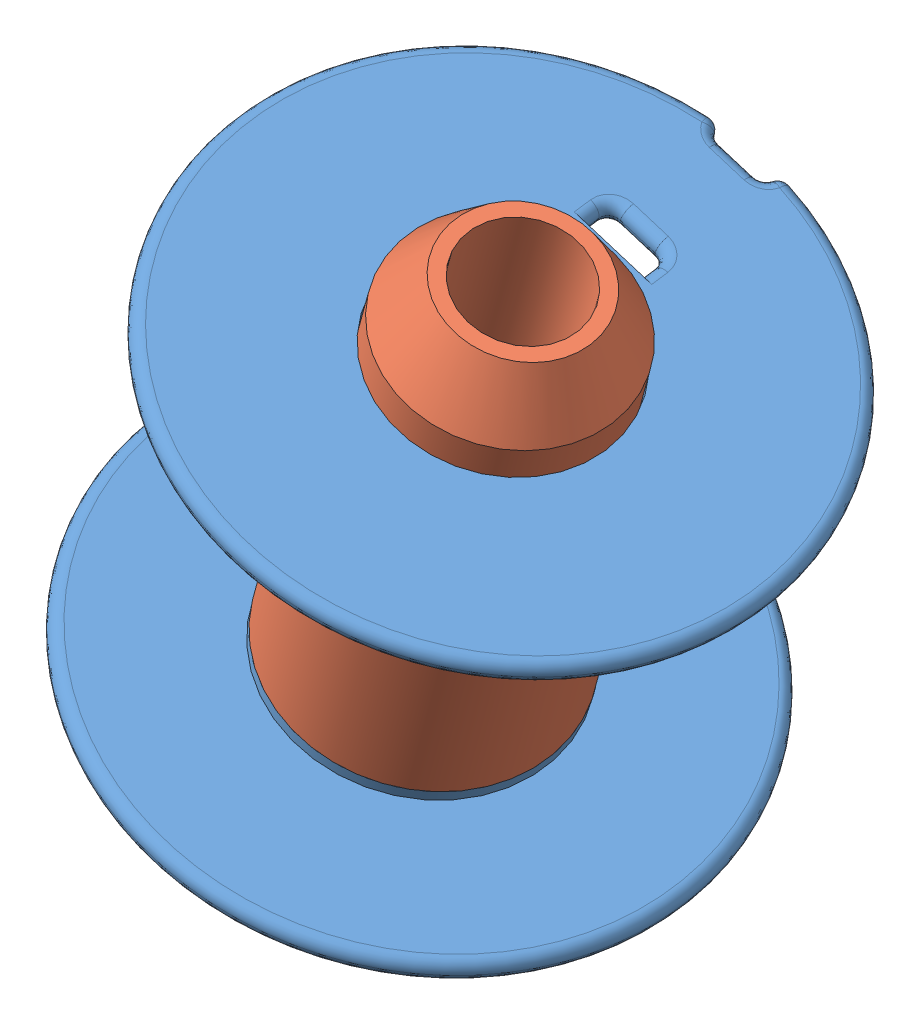
SolidWorks assembly bobbin, configuration Default. Lengths in mm.
Overall size (59.31 60.62 55.89).
3 component instances, 2 part files, 6 mates.
Components (placement in the parent):
- cheek-1: cheek [Default] at (14.8789 38.758 5.9323) x (0.934923 -0.35179 -0.046509) z (-0.00678 -0.14875 0.988852) size (49 3 48.9)
- source_core-1: source_core [Default] at (21.1089 54.9867 8.4162) x (0.454948 -0.30283 0.837447) z (0.816792 -0.23276 -0.527896) size (23 45.66 23)
- cheek-2: cheek [Default] at (27.339 71.2154 10.9002) x (-0.934923 0.35179 0.046509) z (-0.00678 -0.14875 0.988852) size (49 3 48.9)
Mates (geometry in assembly coordinates):
- Coincident1: coincident: plane of cheek-1 through (26.3401 36.5608 5.6803) normal (0.354786 0.924185 0.141455); plane of source_core-1 through (19.9105 37.7295 14.1709) normal (-0.354786 -0.924185 -0.141455)
- Concentric1: concentric: circle of cheek-1; cylinder of source_core-1 through (14.1788 36.9345 5.6532) axis (-0.354786 -0.924185 -0.141455) radius 5.05
- Coincident9: coincident: plane of source_core-1 through (30.9514 66.4902 18.573) normal (0.354786 0.924185 0.141455); plane of cheek-2 through (15.8778 73.4126 11.1521) normal (-0.354786 -0.924185 -0.141455)
- Concentric5: concentric: circle of source_core-1; circle of cheek-2
- Concentric6: concentric: cylinder of source_core-1 through (14.1788 36.9345 5.6532) axis (-0.354786 -0.924185 -0.141455) radius 5.05; point of assembly
- Parallel1: parallel: line of cheek-1 through (12.4985 40.336 -5.4763) axis (0.934923 -0.35179 -0.046509); line of cheek-2 through (27.0622 72.0018 -0.6131) axis (-0.934923 0.35179 0.046509)
